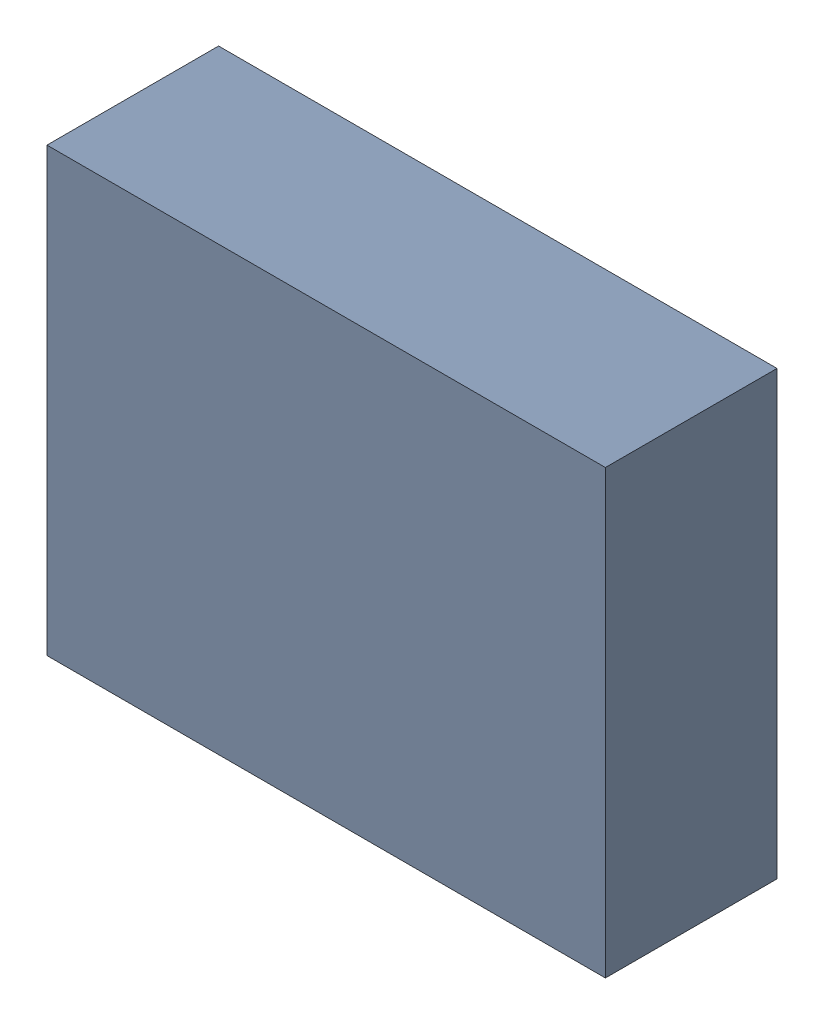
SolidWorks assembly OP1_1, configuration Default. Lengths in mm.
Overall size (5.04 3.99 1.55).
2 component instances, 1 part files, 0 mates.
Components (placement in the parent):
- 407988256-1: 407988256 [Default] at (50.673 11.938 0.2157) size (5.04 3.99 1.55)
  - Extruded_10-1: Extruded_10 [Default] at origin size (5.04 3.99 1.55)
